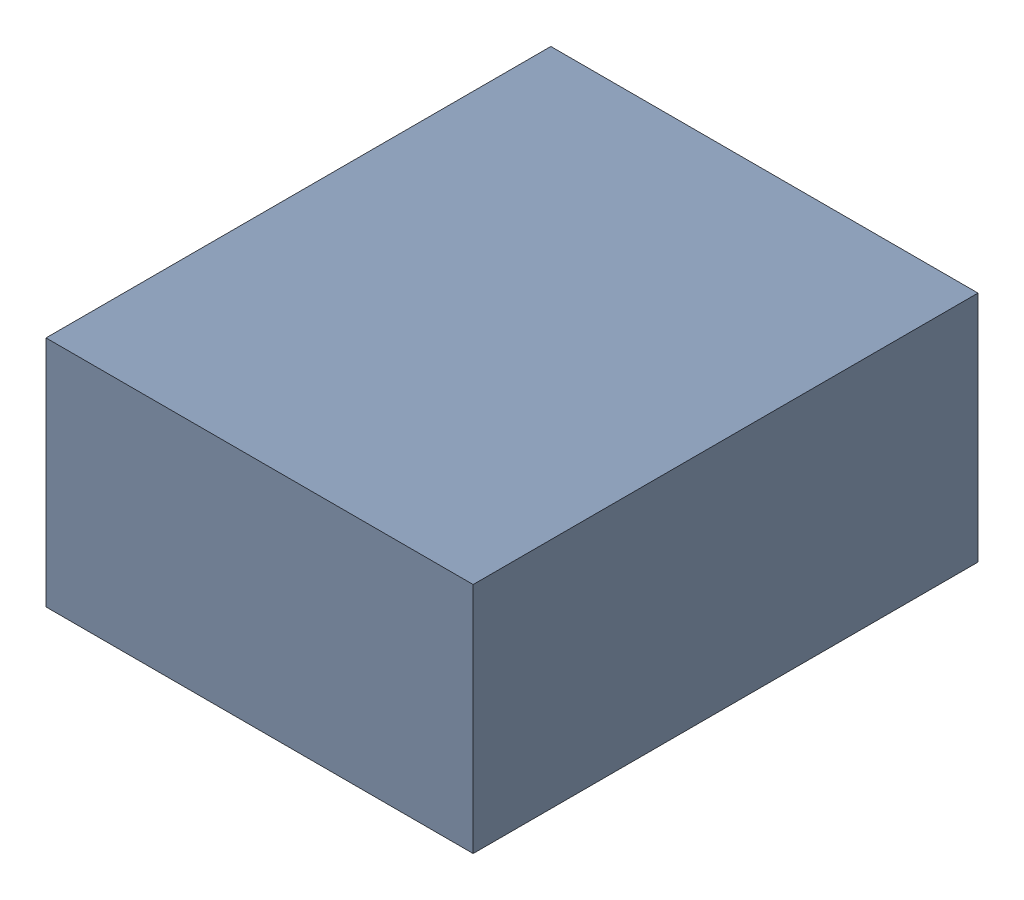
SolidWorks assembly C9, configuration Standard. Lengths in mm.
Overall size (1.1 0.6 1.3).
2 component instances, 1 part files, 0 mates.
Components (placement in the parent):
- 885542240-1: 885542240 [Standard] at (10.65 -3.45 0) size (1.1 0.6 1.3)
  - Extruded_28-1: Extruded_28 [Standard] at origin size (1.1 0.6 1.3)
